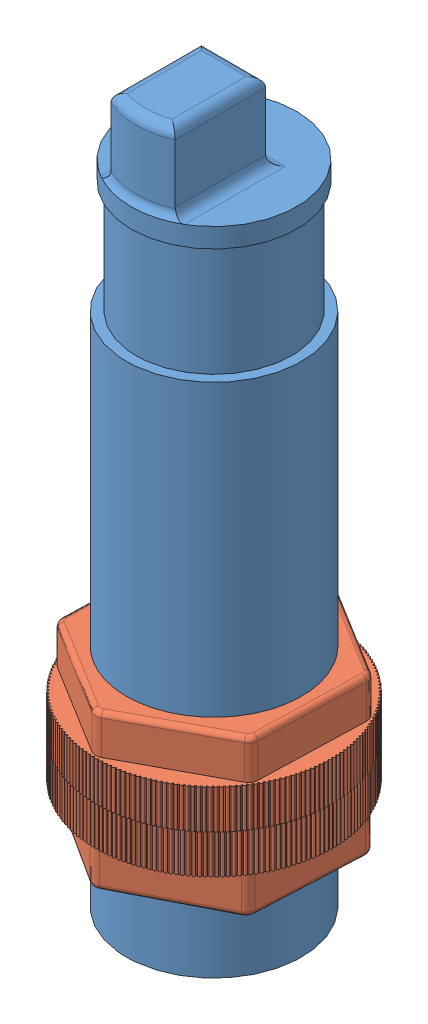
SolidWorks assembly CapteurCapacitif, configuration Predeterminado. Lengths in mm.
Overall size (33.69 74.5 33.69).
3 component instances, 2 part files, 3 mates.
Components (placement in the parent):
- CorpCapteur-1: CorpCapteur [Predeterminado] at (-7.5148 -40.1808 0) size (18 74.5 18)
- EcrouCapteur-1: EcrouCapteur [Predeterminado] at (-7.5148 -24.9716 0) x (0.927522 0 -0.37377) z (0 -1 0) size (24.3 24.3 8)
- EcrouCapteur-2: EcrouCapteur [Predeterminado] at (-7.5148 -24.9716 0) x (0.832687 0 -0.553744) z (0 1 0) size (24.3 24.3 8)
Mates (geometry in assembly coordinates):
- Concéntrica1: concentric anti-aligned: cylinder of CorpCapteur-1 through (-7.5148 12.8192 0) axis (0 -1 0) radius 9; cylinder of EcrouCapteur-1 through (-7.5148 -28.9716 0) axis (0 1 0) radius 9
- Concéntrica2: concentric aligned: cylinder of CorpCapteur-1 through (-7.5148 12.8192 0) axis (0 -1 0) radius 9; cylinder of EcrouCapteur-2 through (-7.5148 -20.9716 0) axis (0 -1 0) radius 9
- Coincidente1: coincident anti-aligned: plane of EcrouCapteur-1 through (-7.5148 -24.9716 0) normal (0 1 0); plane of EcrouCapteur-2 through (-7.5148 -24.9716 0) normal (0 -1 0)
